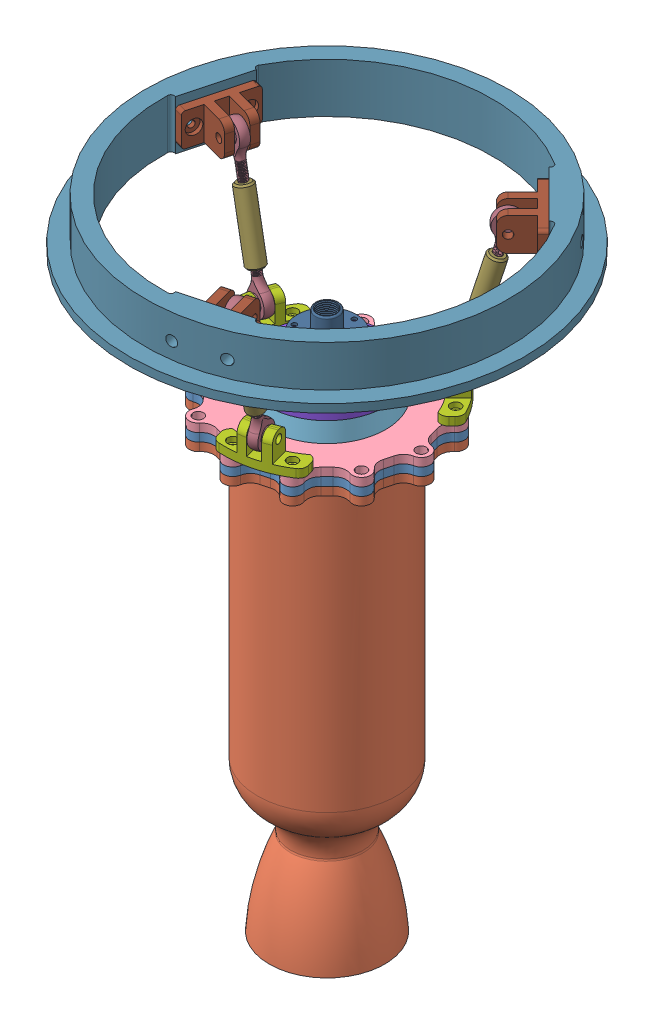
SolidWorks assembly 000014-R02_REMOVE_BEFORE_FLIGHT_ASSM, configuration Default. Lengths in mm.
Overall size (431.05 503.94 431.05).
30 component instances, 14 part files, 26 mates.
Components (placement in the parent):
- 000030-R02_FILM_COOLING_VOLUTE-2: 000030-R02_FILM_COOLING_VOLUTE [Default] at (-8.7806 254.8412 0) x (-0.965926 0 -0.258819) z (0.258819 0 -0.965926) size (156.79 34.88 257.08)
- 000001-R05_RBF_TCA-2: 000001-R05_RBF_TCA [Default] at (-8.7806 -14.701 0) x (0 -1 0) z (0 0 1) size (343.5 185.64 158.75)
- 000015-R05_PINTLE_INJECT_ASSM-1: 000015-R05_PINTLE_INJECT_ASSM [Default] at (86.4435 164.1172 71.5928) x (-0.866025 0 0.5) z (-0.5 0 -0.866025) size (158.75 36.86 158.75)
  - 000033-R01_PINTLE_BOTTOM_PLATE-1: 000033-R01_PINTLE_BOTTOM_PLATE [Default] at (46.67 88.1839 109.6132) size (87.7 15.24 87.7)
  - 000032-R02_PINTLE_MIDDLE_PLATE-1: 000032-R02_PINTLE_MIDDLE_PLATE [Default] at (46.67 92.7382 109.6132) size (158.75 29.57 158.75)
  - 000031-R01_PINTLE_UPPER_PLATE-1: 000031-R01_PINTLE_UPPER_PLATE [Default] at (46.67 125.0393 109.6132) size (90.17 15.27 90.17)
  - MISUMI_MSBH6-20-1: MISUMI_MSBH6-20 [Default] at (8.57 121.0393 109.6132) x (0 -1 0) z (0 0 1) size (31 9 9)
- engine-side-clevis-1: engine-side-clevis [Default] at (-8.7806 273.8912 0) x (0.707107 0 -0.707107) z (0.707107 0 0.707107) size (19.27 25.77 57.15)
- 000012_R04_ASI_ASSEM-1: 000012_R04_ASI_ASSEM [Default] at (-8.7806 251.1654 0) x (-0.959573 0 0.281459) z (-0.281459 0 -0.959573) size (117.68 93.77 117.68)
  - 000011-R02_ASI_TOP-1: 000011-R02_ASI_TOP [Default] at (0 37.9912 0) x (-0.924896 0 -0.380219) z (0.380219 0 -0.924896) size (90.17 60.14 90.17)
  - 000011-R02_ASI_BOTTOM-1: 000011-R02_ASI_BOTTOM [Default] at (0 4.4632 0) x (0.915191 0 -0.40302) z (0.40302 0 0.915191) size (30.48 24.13 30.48)
  - 000010-R02_ASI-1: 000010-R02_ASI [Default] at (0 63.3912 0) x (-0.133168 0 -0.991093) z (0.991093 0 -0.133168) size (45.72 18.88 45.72)
- 000061-R01_THRUST_MOUNT_ASSM-6: 000061-R01_THRUST_MOUNT_ASSM [Default] at (111.4343 329.5064 -151.8672) x (-0.196474 0.979436 -0.045863) z (0.562368 0.15088 0.813005) size (122.1 89.38 60.95) (flexible)
  - 000029-R01_LAUNCH_MOUNT_CLEVIS-1: 000029-R01_LAUNCH_MOUNT_CLEVIS [Default] at (62.1337 58.6887 43.4668) x (0.979436 -0.133943 0.15088) z (-0.171358 -0.157515 0.972536) size (31.75 38.1 50.8)
  - THREADED_ROD-1: THREADED_ROD [Default] at (45.0805 88.7224 45.3265) x (0.280946 0.444914 -0.850365) z (0.288612 0.805871 0.516987) size (12.7 50.8 12.7)
  - 8405K111_THRUST-RATED BALL JOINT ROD END-1: 8405K111_THRUST-RATED BALL JOINT ROD END [8405K111] at (-12.2705 113.2011 39.186) x (0.364505 0.906954 0.211118) z (-0.171358 -0.157515 0.972536) size (19.88 46.6 9.53)
  - 8405K111_THRUST-RATED BALL JOINT ROD END-2: 8405K111_THRUST-RATED BALL JOINT ROD END [8405K111] at (49.9702 86.6353 45.85) x (-0.364505 -0.906954 -0.211118) z (-0.171358 -0.157515 0.972536) size (19.88 46.6 9.53)
- engine-side-clevis-6: engine-side-clevis [Default] at (-8.7806 273.8912 0) x (0.258819 0 0.965926) z (-0.965926 0 0.258819) size (19.27 25.77 57.15)
- engine-side-clevis-7: engine-side-clevis [Default] at (-8.7806 273.8912 0) x (-0.965926 0 -0.258819) z (0.258819 0 -0.965926) size (19.27 25.77 57.15)
- 000061-R01_THRUST_MOUNT_ASSM-7: 000061-R01_THRUST_MOUNT_ASSM [Default] at (62.6329 329.5064 180.0427) x (0.137955 0.979436 -0.14722) z (-0.985267 0.15088 0.080522) size (122.1 89.38 60.95) (flexible)
  - 000029-R01_LAUNCH_MOUNT_CLEVIS-1: 000029-R01_LAUNCH_MOUNT_CLEVIS [Default] at (62.1337 58.6887 43.4668) x (0.979436 -0.133943 0.15088) z (-0.171358 -0.157515 0.972536) size (31.75 38.1 50.8)
  - THREADED_ROD-1: THREADED_ROD [Default] at (38.0046 91.7425 44.5689) x (-0.001409 0.240201 0.970722) z (-0.402772 -0.888639 0.219305) size (12.7 50.8 12.7)
  - 8405K111_THRUST-RATED BALL JOINT ROD END-1: 8405K111_THRUST-RATED BALL JOINT ROD END [8405K111] at (-12.2705 113.2011 39.186) x (0.364505 0.906954 0.211118) z (-0.171358 -0.157515 0.972536) size (19.88 46.6 9.53)
  - 8405K111_THRUST-RATED BALL JOINT ROD END-2: 8405K111_THRUST-RATED BALL JOINT ROD END [8405K111] at (49.9702 86.6353 45.85) x (-0.364505 -0.906954 -0.211118) z (-0.171358 -0.157515 0.972536) size (19.88 46.6 9.53)
- 000061-R01_THRUST_MOUNT_ASSM-8: 000061-R01_THRUST_MOUNT_ASSM [Default] at (-200.4089 329.5064 -28.1755) x (0.058519 0.979436 0.193083) z (0.4229 0.15088 -0.893527) size (128.32 90.23 60.95) (flexible)
  - 000029-R01_LAUNCH_MOUNT_CLEVIS-1: 000029-R01_LAUNCH_MOUNT_CLEVIS [Default] at (62.1337 58.6887 43.4668) x (-0.979436 0.133943 -0.15088) z (0.171358 0.157515 -0.972536) size (31.75 38.1 50.8)
  - THREADED_ROD-1: THREADED_ROD [Default] at (38.0048 91.7424 44.5689) x (0.186107 0.194437 -0.963098) z (0.3572 0.899761 0.250674) size (12.7 50.8 12.7)
  - 8405K111_THRUST-RATED BALL JOINT ROD END-1: 8405K111_THRUST-RATED BALL JOINT ROD END [8405K111] at (-12.2705 113.2011 39.186) x (0.364505 0.906954 0.211118) z (-0.171358 -0.157515 0.972536) size (19.88 46.6 9.53)
  - 8405K111_THRUST-RATED BALL JOINT ROD END-2: 8405K111_THRUST-RATED BALL JOINT ROD END [8405K111] at (49.9702 86.6353 45.85) x (0.364505 0.906954 0.211118) z (0.171358 0.157515 -0.972536) size (19.88 46.6 9.53)
- 000066-R01_THRUST_MOUNT-1: 000066-R01_THRUST_MOUNT [Default] at (-8.7806 370.0097 0) x (0.707107 0 -0.707107) z (0.707107 0 0.707107) size (304.8 38.1 304.8)
Mates (geometry in assembly coordinates):
- Concentric22: concentric aligned: cylinder of 000030-R02_FILM_COOLING_VOLUTE-2 through (63.6094 267.5412 0) axis (0 1 0) radius 4; cylinder of 000001-R05_RBF_TCA-2 through (63.6094 261.1912 0) axis (0 1 0) radius 4
- Coincident11: coincident anti-aligned: plane of 000030-R02_FILM_COOLING_VOLUTE-2 through (-66.4686 261.1912 -15.4575) normal (0 -1 0); plane of 000001-R05_RBF_TCA-2 through (70.5944 261.1912 0) normal (0 1 0)
- Concentric40: concentric anti-aligned: cylinder of 000030-R02_FILM_COOLING_VOLUTE-2 through (-8.7806 299.8925 0) axis (0 1 0) radius 43.848; cylinder of 000015-R05_PINTLE_INJECT_ASSM-1/000033-R01_PINTLE_BOTTOM_PLATE-1 through (-8.7806 252.3012 0) axis (0 -1 0) radius 43.848
- Coincident29: coincident anti-aligned: plane of 000030-R02_FILM_COOLING_VOLUTE-2 through (-51.1345 267.5412 -11.3487) normal (0 1 0); plane of 000015-R05_PINTLE_INJECT_ASSM-1/000032-R02_PINTLE_MIDDLE_PLATE-1 through (-77.5213 267.5412 39.6875) normal (0 -1 0)
- Coincident65: coincident anti-aligned: plane of 000015-R05_PINTLE_INJECT_ASSM-1/000032-R02_PINTLE_MIDDLE_PLATE-1 through (-77.5213 273.8912 39.6875) normal (0 1 0); plane of engine-side-clevis-1 through (-8.7806 273.8912 0) normal (0 -1 0)
- Coincident70: coincident anti-aligned: plane of 000015-R05_PINTLE_INJECT_ASSM-1/000031-R01_PINTLE_UPPER_PLATE-1 through (-16.4795 289.1566 4.445) normal (0 1 0); plane of 000012_R04_ASI_ASSEM-1/000011-R02_ASI_TOP-1 through (36.0575 289.1566 4.7127) normal (0 -1 0)
- Concentric88: concentric aligned: cylinder of 000015-R05_PINTLE_INJECT_ASSM-1/000031-R01_PINTLE_UPPER_PLATE-1 through (6.7161 289.1566 -34.8061) axis (0 1 0) radius 5; cylinder of 000012_R04_ASI_ASSEM-1/000011-R02_ASI_TOP-1 through (6.7161 294.2366 -34.8061) axis (0 1 0) radius 4.953
- Concentric89: concentric aligned: cylinder of 000015-R05_PINTLE_INJECT_ASSM-1/000031-R01_PINTLE_UPPER_PLATE-1 through (24.215 289.1566 -19.05) axis (0 1 0) radius 5; cylinder of 000012_R04_ASI_ASSEM-1/000011-R02_ASI_TOP-1 through (24.215 294.2366 -19.05) axis (0 1 0) radius 4.953
- Concentric91: concentric anti-aligned: cylinder of 000030-R02_FILM_COOLING_VOLUTE-2 through (53.911 267.5412 -36.195) axis (0 1 0) radius 4; cylinder of 000015-R05_PINTLE_INJECT_ASSM-1/000032-R02_PINTLE_MIDDLE_PLATE-1 through (53.911 267.5412 -36.195) axis (0 -1 0) radius 4
- Concentric93: concentric anti-aligned: cylinder of 000001-R05_RBF_TCA-2 through (53.911 261.1912 36.195) axis (0 1 0) radius 4; cylinder of 000015-R05_PINTLE_INJECT_ASSM-1/000032-R02_PINTLE_MIDDLE_PLATE-1 through (53.911 267.5412 36.195) axis (0 -1 0) radius 4
- Concentric95: concentric aligned: cylinder of engine-side-clevis-1 through (21.7512 292.9412 -70.9429) axis (0.707107 0 0.707107) radius 3.175; cylinder of 000061-R01_THRUST_MOUNT_ASSM-6/8405K111_THRUST-RATED BALL JOINT ROD END-1 through (38.5892 292.9412 -54.1049) axis (0.707107 0 0.707107) radius 3.175
- Coincident73: coincident aligned: plane of engine-side-clevis-1 through (-8.7806 273.8912 0) normal (0.707107 0 0.707107); plane of 000061-R01_THRUST_MOUNT_ASSM-6/8405K111_THRUST-RATED BALL JOINT ROD END-1 through (44.9582 308.2382 -53.7388) normal (0.707107 0 0.707107)
- Concentric97: concentric anti-aligned: cylinder of 000015-R05_PINTLE_INJECT_ASSM-1/000032-R02_PINTLE_MIDDLE_PLATE-1 through (27.4144 267.5412 -62.6916) axis (0 -1 0) radius 4; cylinder of engine-side-clevis-1 through (27.4144 280.2412 -62.6916) axis (0 1 0) radius 4
- Concentric98: concentric anti-aligned: cylinder of 000015-R05_PINTLE_INJECT_ASSM-1/000032-R02_PINTLE_MIDDLE_PLATE-1 through (53.911 267.5412 -36.195) axis (0 -1 0) radius 4; cylinder of engine-side-clevis-1 through (53.911 280.2412 -36.195) axis (0 1 0) radius 2.25
- Coincident75: coincident anti-aligned: plane of 000015-R05_PINTLE_INJECT_ASSM-1/000032-R02_PINTLE_MIDDLE_PLATE-1 through (-77.5213 273.8912 39.6875) normal (0 1 0); plane of engine-side-clevis-1 through (-8.7806 273.8912 0) normal (0 -1 0)
- Concentric100: concentric aligned: cylinder of engine-side-clevis-7 through (-85.4848 292.9412 9.0302) axis (0.258819 0 -0.965926) radius 3.175; cylinder of 000061-R01_THRUST_MOUNT_ASSM-8/8405K111_THRUST-RATED BALL JOINT ROD END-1 through (-79.3217 292.9412 -13.9709) axis (0.258819 0 -0.965926) radius 3.175
- Coincident76: coincident aligned: plane of engine-side-clevis-7 through (-8.7806 273.8912 0) normal (0.258819 0 -0.965926); plane of 000061-R01_THRUST_MOUNT_ASSM-8/8405K111_THRUST-RATED BALL JOINT ROD END-1 through (-82.1891 308.2382 -19.6698) normal (0.258819 0 -0.965926)
- Coincident78: coincident aligned: plane of engine-side-clevis-6 through (-8.7806 273.8912 0) normal (-0.965926 0 0.258819); plane of 000061-R01_THRUST_MOUNT_ASSM-7/8405K111_THRUST-RATED BALL JOINT ROD END-1 through (10.8892 308.2382 73.4086) normal (-0.965926 0 0.258819)
- Concentric101: concentric aligned: cylinder of engine-side-clevis-6 through (37.3919 292.9412 61.9127) axis (-0.965926 0 0.258819) radius 3.175; cylinder of 000061-R01_THRUST_MOUNT_ASSM-7/8405K111_THRUST-RATED BALL JOINT ROD END-1 through (14.3908 292.9412 68.0759) axis (-0.965926 0 0.258819) radius 3.175
- Coincident79: coincident anti-aligned: plane of 000061-R01_THRUST_MOUNT_ASSM-6/000029-R01_LAUNCH_MOUNT_CLEVIS-1 through (76.5319 389.0597 -85.3124) normal (0.707107 0 -0.707107); plane of 000066-R01_THRUST_MOUNT-1 through (58.5714 370.0097 -103.2729) normal (-0.707107 0 0.707107)
- Coincident80: coincident anti-aligned: plane of 000061-R01_THRUST_MOUNT_ASSM-7/000029-R01_LAUNCH_MOUNT_CLEVIS-1 through (22.446 389.0597 116.539) normal (0.258819 0 0.965926); plane of 000066-R01_THRUST_MOUNT-1 through (46.9805 370.0097 109.9649) normal (-0.258819 0 -0.965926)
- Coincident81: coincident anti-aligned: plane of 000061-R01_THRUST_MOUNT_ASSM-8/000029-R01_LAUNCH_MOUNT_CLEVIS-1 through (-125.3195 389.0597 -31.2265) normal (-0.965926 0 -0.258819); plane of 000066-R01_THRUST_MOUNT-1 through (-131.8935 370.0097 -6.692) normal (0.965926 0 0.258819)
- Concentric102: concentric anti-aligned: cylinder of 000001-R05_RBF_TCA-2 through (-8.7806 221.7735 0) axis (0 1 0) radius 53.373; cylinder of 000066-R01_THRUST_MOUNT-1 through (-8.7806 408.1097 0) axis (0 -1 0) radius 152.4
- Concentric104: concentric aligned: cylinder of 000061-R01_THRUST_MOUNT_ASSM-6/000029-R01_LAUNCH_MOUNT_CLEVIS-1 through (84.3896 389.0597 -68.4745) axis (-0.707107 0 0.707107) radius 2.5527; cylinder of 000066-R01_THRUST_MOUNT-1 through (88.8797 389.0597 -72.9646) axis (-0.707107 0 0.707107) radius 4
- Concentric107: concentric aligned: cylinder of 000061-R01_THRUST_MOUNT_ASSM-7/000029-R01_LAUNCH_MOUNT_CLEVIS-1 through (3.935 389.0597 114.9249) axis (-0.258819 0 -0.965926) radius 2.5527; cylinder of 000066-R01_THRUST_MOUNT-1 through (5.5785 389.0597 121.0586) axis (-0.258819 0 -0.965926) radius 4
- Concentric108: concentric aligned: cylinder of 000061-R01_THRUST_MOUNT_ASSM-8/000029-R01_LAUNCH_MOUNT_CLEVIS-1 through (-114.6663 389.0597 -46.4505) axis (0.965926 0 0.258819) radius 2.5527; cylinder of 000066-R01_THRUST_MOUNT-1 through (-120.7999 389.0597 -48.094) axis (0.965926 0 0.258819) radius 4
